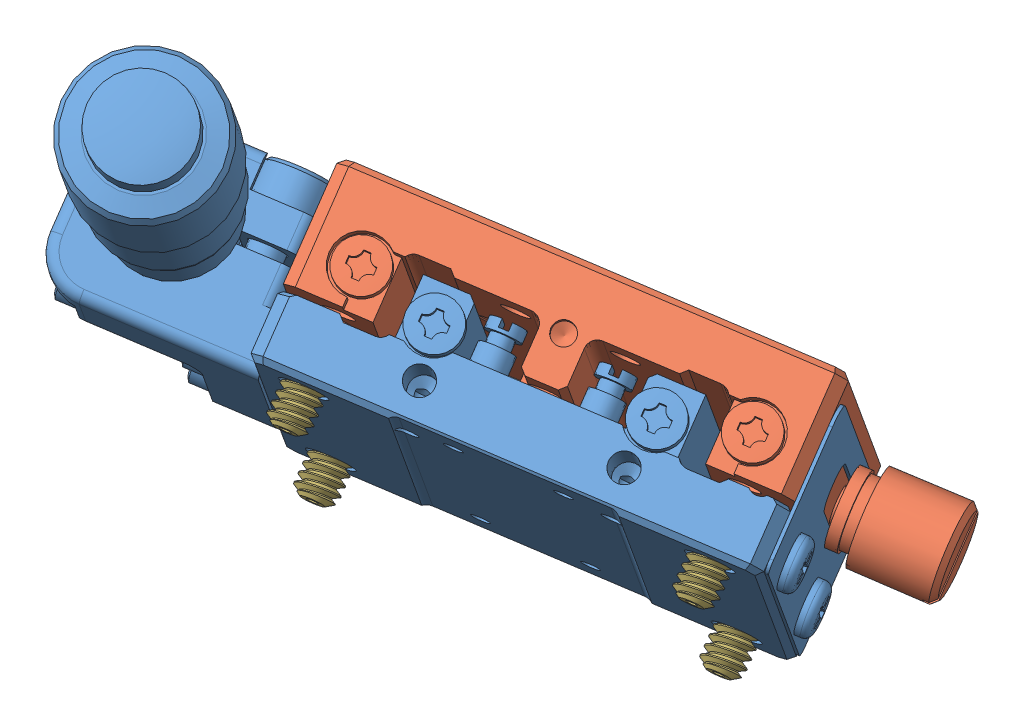
SolidWorks assembly Stage_122-0070_with_bolts, configuration Default. Lengths in mm.
Overall size (85.38 72.86 78.23).
6 component instances, 3 part files, 11 mates.
Components (placement in the parent):
- TSD-401SUU-C1B-S07-1: TSD-401SUU-C1B-S07 [Default] at (24.0193 -47.1553 -10.1213) x (0.873594 -0.248588 -0.418375) z (-0.156541 0.670463 -0.72524) size (59.6 67 15.55)
- TSD-401SUU-C1B-S08-1: TSD-401SUU-C1B-S08 [Default] at (21.602 -36.4527 -21.767) x (0.873594 -0.248588 -0.418375) z (-0.156541 0.670463 -0.72524) size (64.1 43.23 10.9)
- 6-32_L=0.19inch-1: 6-32_L=0.19inch [93235A142] at (3.3467 -56.4939 -9.7939) x (0.986154 0.065421 -0.152379) z (0.156541 -0.670463 0.72524) size (5.74 5.74 8.58)
- 6-32_L=0.19inch-2: 6-32_L=0.19inch [93235A142] at (17.9768 -34.2988 7.5669) x (0.986154 0.065421 -0.152379) z (0.156541 -0.670463 0.72524) size (5.74 5.74 8.58)
- 6-32_L=0.19inch-3: 6-32_L=0.19inch [93235A142] at (45.7134 -42.1915 -5.7165) x (0.986154 0.065421 -0.152379) z (0.156541 -0.670463 0.72524) size (5.74 5.74 8.58)
- 6-32_L=0.19inch-4: 6-32_L=0.19inch [93235A142] at (31.0833 -64.3866 -23.0773) x (0.986154 0.065421 -0.152379) z (0.156541 -0.670463 0.72524) size (5.74 5.74 8.58)
Mates (geometry in assembly coordinates):
- Concentric1: concentric anti-aligned: circle of TSD-401SUU-C1B-S07-1; circle of 6-32_L=0.19inch-1
- Concentric2: concentric anti-aligned: circle of TSD-401SUU-C1B-S07-1; circle of 6-32_L=0.19inch-2
- Concentric3: concentric anti-aligned: circle of TSD-401SUU-C1B-S07-1; circle of 6-32_L=0.19inch-3
- Concentric4: concentric anti-aligned: circle of TSD-401SUU-C1B-S07-1; circle of 6-32_L=0.19inch-4
- Coincident1: coincident anti-aligned: plane of TSD-401SUU-C1B-S07-1 through (25.9142 -62.6868 -26.957) normal (-0.156541 0.670463 -0.72524); plane of 6-32_L=0.19inch-4 through (30.3377 -61.1935 -26.5313) normal (0.156541 -0.670463 0.72524)
- Coincident2: coincident anti-aligned: plane of TSD-401SUU-C1B-S07-1 through (40.5444 -40.4917 -9.5962) normal (-0.156541 0.670463 -0.72524); plane of 6-32_L=0.19inch-3 through (44.9679 -38.9984 -9.1704) normal (0.156541 -0.670463 0.72524)
- Coincident3: coincident anti-aligned: plane of TSD-401SUU-C1B-S07-1 through (12.8078 -32.599 3.6872) normal (-0.156541 0.670463 -0.72524); plane of 6-32_L=0.19inch-2 through (17.2313 -31.1057 4.113) normal (0.156541 -0.670463 0.72524)
- Coincident4: coincident anti-aligned: plane of TSD-401SUU-C1B-S07-1 through (-1.8224 -54.7941 -13.6736) normal (-0.156541 0.670463 -0.72524); plane of 6-32_L=0.19inch-1 through (2.6011 -53.3008 -13.2479) normal (0.156541 -0.670463 0.72524)
- Coincident6: coincident: plane of TSD-401SUU-C1B-S07-1 through (40.4535 -47.3334 -23.7428) normal (-0.873594 0.248588 0.418375); plane of TSD-401SUU-C1B-S08-1 through (40.6346 -48.1092 -22.9036) normal (0.873594 -0.248588 -0.418375)
- Coincident7: coincident: plane of TSD-401SUU-C1B-S07-1 through (32.6484 -30.4119 -2.2223) normal (0.460792 0.699058 0.546798); plane of TSD-401SUU-C1B-S08-1 through (31.4928 -25.3624 -7.704) normal (0.460792 0.699058 0.546798)
- Distance1: distance = 0.5 mm anti-aligned: plane of TSD-401SUU-C1B-S08-1 through (21.9378 -42.4319 -14.4058) normal (0.156541 -0.670463 0.72524); plane of TSD-401SUU-C1B-S07-1 through (29.0048 -44.7559 -17.3902) normal (-0.156541 0.670463 -0.72524)
